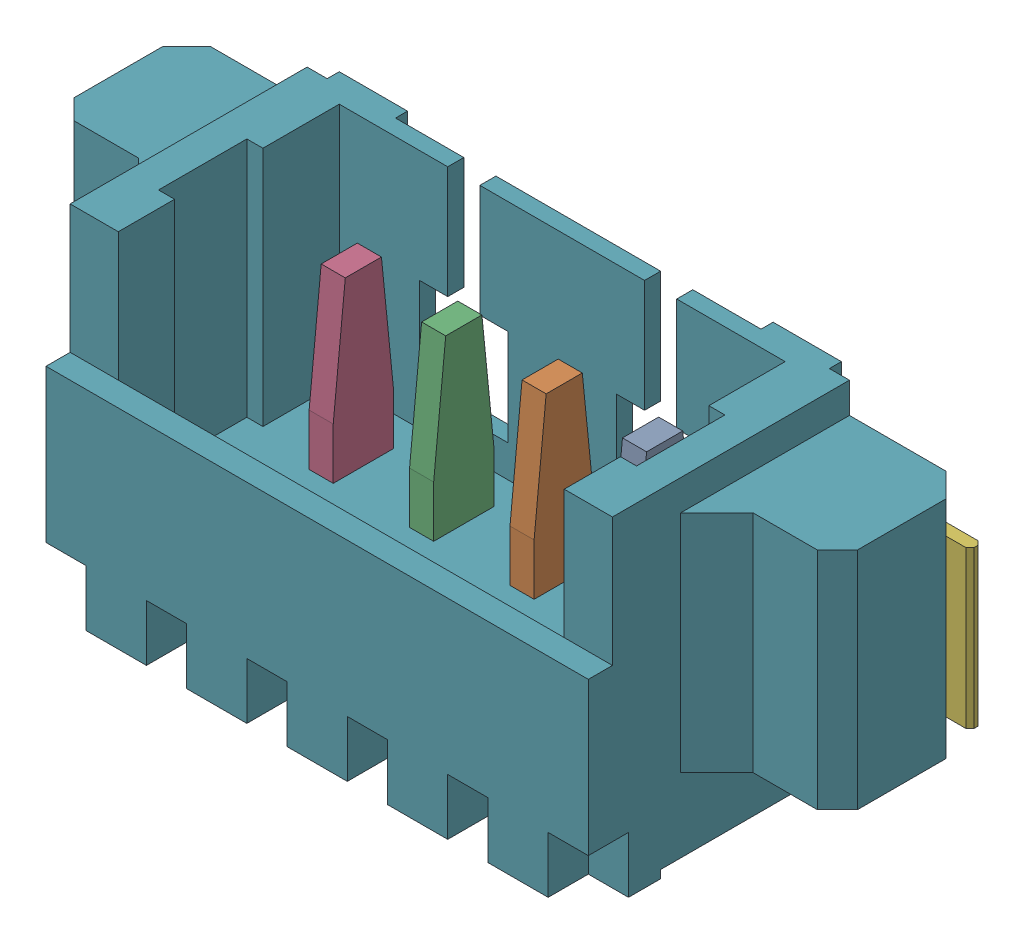
SolidWorks assembly J12, configuration Default. Lengths in mm.
Overall size (9.75 5.4 3.41).
8 component instances, 3 part files, 0 mates.
Components (placement in the parent):
- 653104131822-1: 653104131822 [Default] at (115.8001 84.1 1.69) x (-1 0 0) z (0 0 1) size (9.75 5.4 3.41)
  - 6531xx131822_PIN_2-1: 6531xx131822_PIN_2 [Default] at (-1.875 2.7 -0.425) x (1 0 0) z (0 -1 0) size (0.3 1.48 4.54)
  - 6531xx131822_PIN_2-2: 6531xx131822_PIN_2 [Default] at (-0.625 2.7 -0.425) x (1 0 0) z (0 -1 0) size (0.3 1.48 4.54)
  - 6531xx131822_PIN_2-3: 6531xx131822_PIN_2 [Default] at (0.625 2.7 -0.425) x (1 0 0) z (0 -1 0) size (0.3 1.48 4.54)
  - 6531xx131822_PIN_2-4: 6531xx131822_PIN_2 [Default] at (1.875 2.7 -0.425) x (1 0 0) z (0 -1 0) size (0.3 1.48 4.54)
  - 6531xx131822_PIN_FLANGE_2-1: 6531xx131822_PIN_FLANGE_2 [Default] at (3.75 -0.045 -1.05) size (1.25 1.95 1.4)
  - 6531xx131822_PIN_FLANGE_2-2: 6531xx131822_PIN_FLANGE_2 [Default] at (-3.75 -0.045 -1.05) x (-1 0 0) z (0 0 1) size (1.25 1.95 1.4)
  - 653104131822-1: 653104131822 [Default] at origin size (9.75 4.2 3.4)
